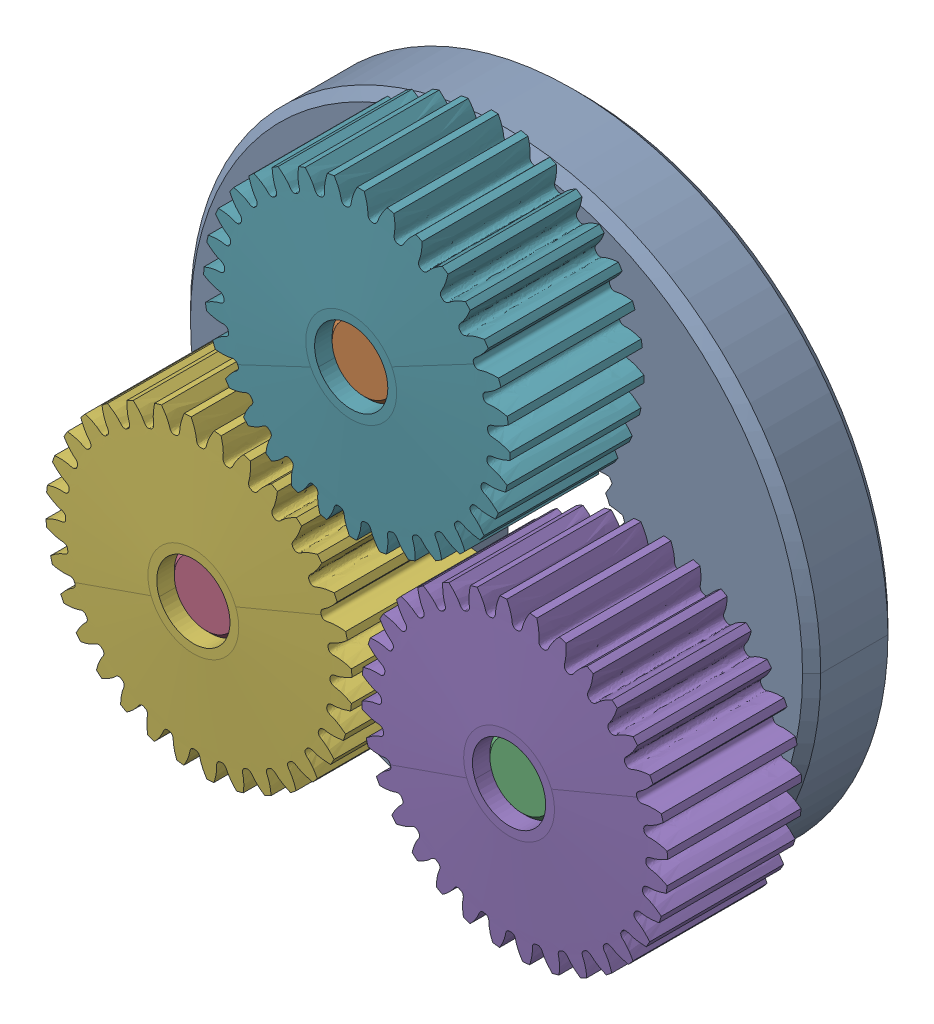
SolidWorks assembly 217-2625-100.step, configuration Default. Lengths in mm.
Overall size (39.22 38.88 12.7).
7 component instances, 3 part files, 0 mates.
Components (placement in the parent):
- 217-2625-008 Rev1.step-1: 217-2625-008 Rev1.step [Default] at origin size (34.7 34.7 4.7)
- 217-2625-010 Rev1.step-1: 217-2625-010 Rev1.step [Default] at (0 10.193 3.65) x (0.999813 0.019336 0) z (0 0 1) size (4 4 12)
- 217-2625-010 Rev1.step-2: 217-2625-010 Rev1.step [Default] at (8.691 -5.3258 3.65) size (4 4 12)
- 217-2625-010 Rev1.step-3: 217-2625-010 Rev1.step [Default] at (-8.691 -5.3258 3.65) size (4 4 12)
- 217-2625-005 Rev1_Planet_Revolving_Follower01.step-1: 217-2625-005 Rev1_Planet_Revolving_Follower01.step [Default] at (8.691 -5.3258 6.35) x (0.932816 0.360354 0) z (0 0 1) size (16.89 16.89 8)
- 217-2625-005 Rev1_Planet_Revolving_Follower01.step-2: 217-2625-005 Rev1_Planet_Revolving_Follower01.step [Default] at (-8.691 -5.3258 6.35) x (-0.932788 -0.360426 0) z (0 0 1) size (16.89 16.89 8)
- 217-2625-005 Rev1_Planet_Revolving_Follower01.step-3: 217-2625-005 Rev1_Planet_Revolving_Follower01.step [Default] at (0 10.193 6.35) x (0.893583 0.448898 0) z (0 0 1) size (16.89 16.89 8)
